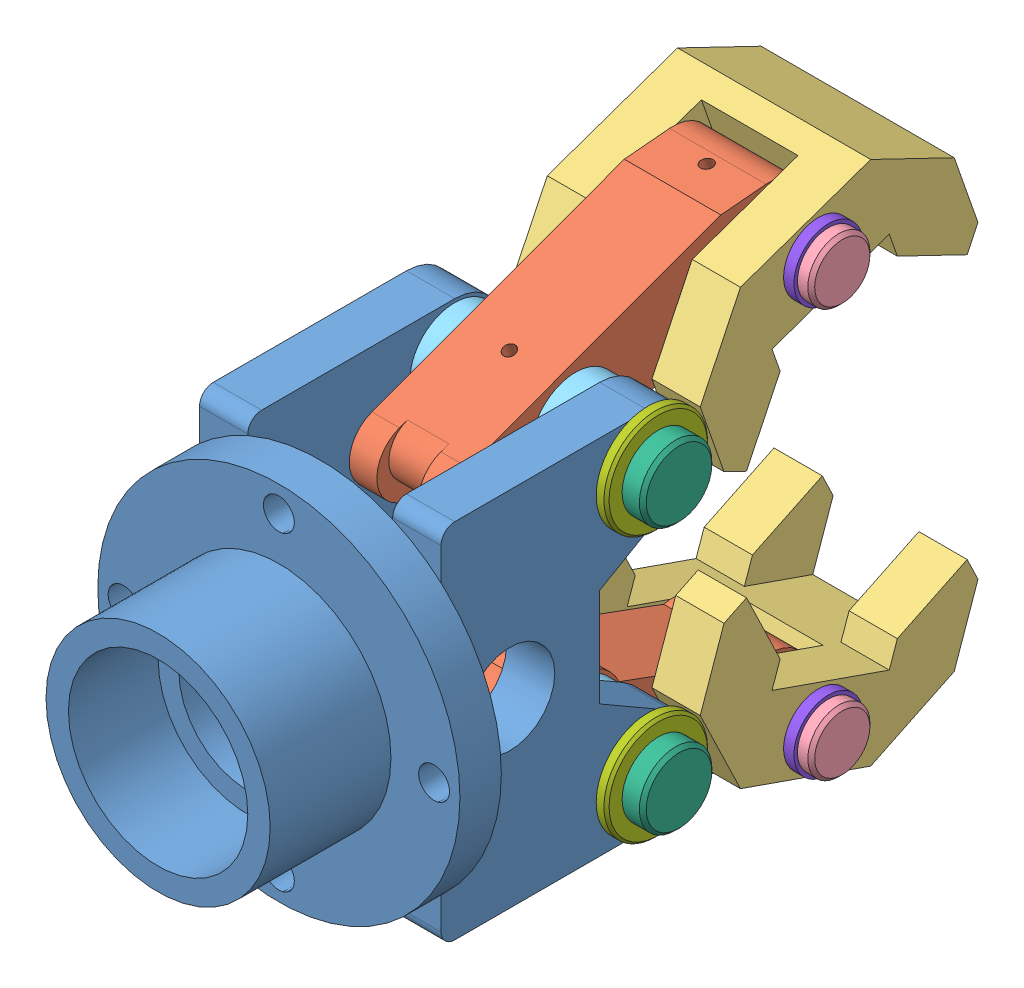
SolidWorks assembly joint7, configuration 默认. Lengths in mm.
Overall size (105 164.84 211.36).
17 component instances, 8 part files, 0 mates.
Components (placement in the parent):
- 14-1: 14 [默认] at origin size (105 105 121)
- 18-1: 18 [默认] at (0 38.5 -107) x (0 0.344424 -0.938814) z (1 0 0) size (109.57 29 28)
- 19-1: 19 [默认] at (0 69.5489 -159.698) x (0 0.330078 -0.943954) z (1 0 0) size (78 45 56)
- 22-1: 22 [默认] at (35 59.1654 -163.3289) x (0 -0.811761 -0.583989) z (-1 0 0) size (18 18 66)
- 24-1: 24 [默认] at (-21 38.5 -107) x (0 -0.533782 -0.845622) z (1 0 0) size (26 26 7)
- 25-1: 25 [默认] at (44 38.5 -107) x (-1 0 0) z (0 -0.659078 -0.752075) size (82 21 21)
- 24-2: 24 [默认] at (21 38.5 -107) x (0 -0.699829 -0.71431) z (-1 0 0) size (26 26 7)
- 26-1: 26 [默认] at (26.3555 38.5 -107) x (0 -0.33616 0.941805) z (0 0.941805 0.33616) size (30 3 30)
- 23-1: 23 [默认] at (28 59.1654 -163.3289) x (0 -0.043815 -0.99904) z (1 0 0) size (20 20 3)
- 19-2: 19 [默认] at (0 -69.5489 -159.698) x (0 -0.330078 -0.943954) z (-1 0 0) size (78 45 56)
- 18-2: 18 [默认] at (0 -38.5 -107) x (0 -0.344424 -0.938814) z (-1 0 0) size (109.57 29 28)
- 22-2: 22 [默认] at (35 -59.1654 -163.3289) x (0 -0.811761 0.583989) z (-1 0 0) size (18 18 66)
- 23-2: 23 [默认] at (31 -59.1654 -163.3289) x (0 0.043815 -0.99904) z (-1 0 0) size (20 20 3)
- 25-2: 25 [默认] at (44 -38.5 -107) x (-1 0 0) z (0 -0.659078 0.752075) size (82 21 21)
- 26-2: 26 [默认] at (26.3555 -38.5 -107) x (0 0.33616 0.941805) z (0 0.941805 -0.33616) size (30 3 30)
- 24-3: 24 [默认] at (14 -38.5 -107) x (0 0.699829 -0.71431) z (1 0 0) size (26 26 7)
- 24-4: 24 [默认] at (-14 -38.5 -107) x (0 0.533782 -0.845622) z (-1 0 0) size (26 26 7)
